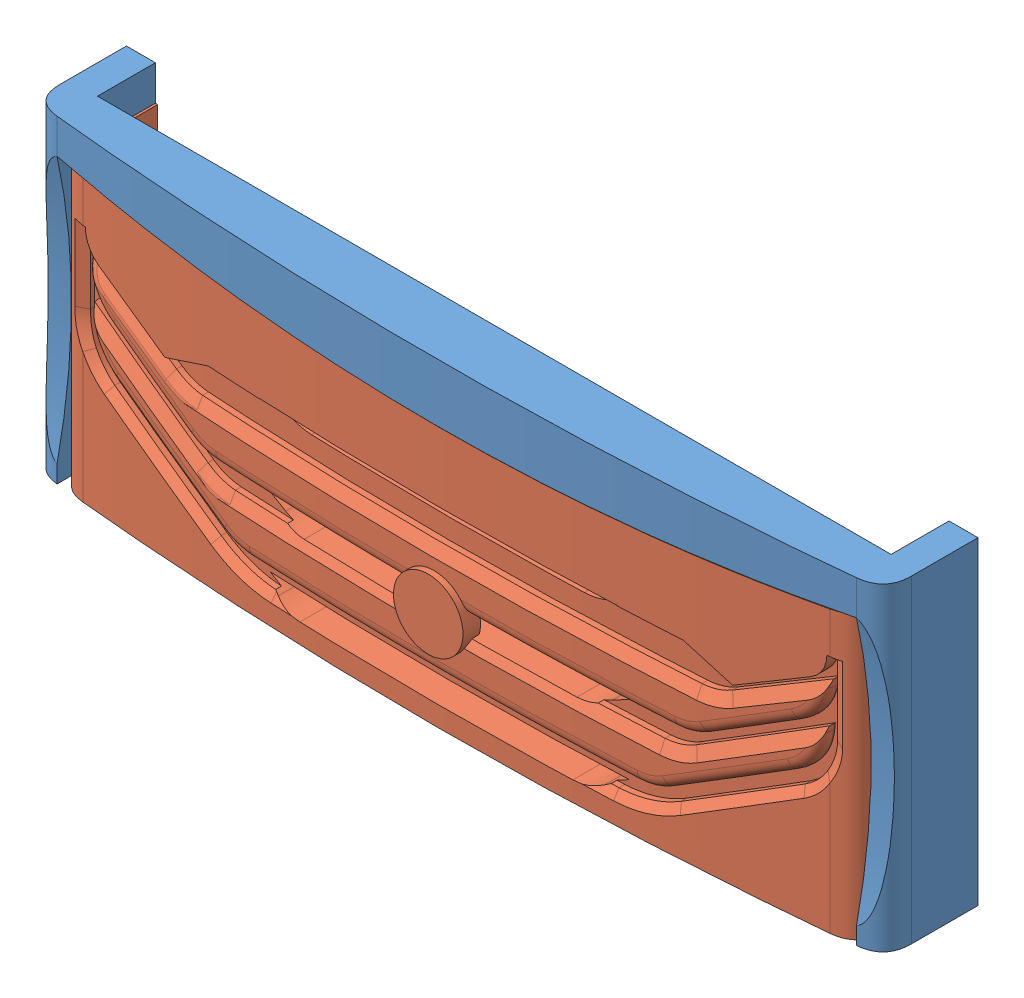
SolidWorks assembly 1_14ashokleyland_Assembly, configuration Default. Lengths in mm.
Overall size (153.22 70.2 37.46).
2 component instances, 2 part files, 0 mates.
Components (placement in the parent):
- 1_14 ashok leyland AVTR-1: 1_14 ashok leyland AVTR [Default] at (33.1901 52.0765 149.2178) size (153.22 70.16 37.46)
- 1_14 ashok leyland AVTR_small_cowl-1: 1_14 ashok leyland AVTR_small_cowl [Default] at (33.5522 52.043 149.1993) size (138.07 66.99 22.55)
